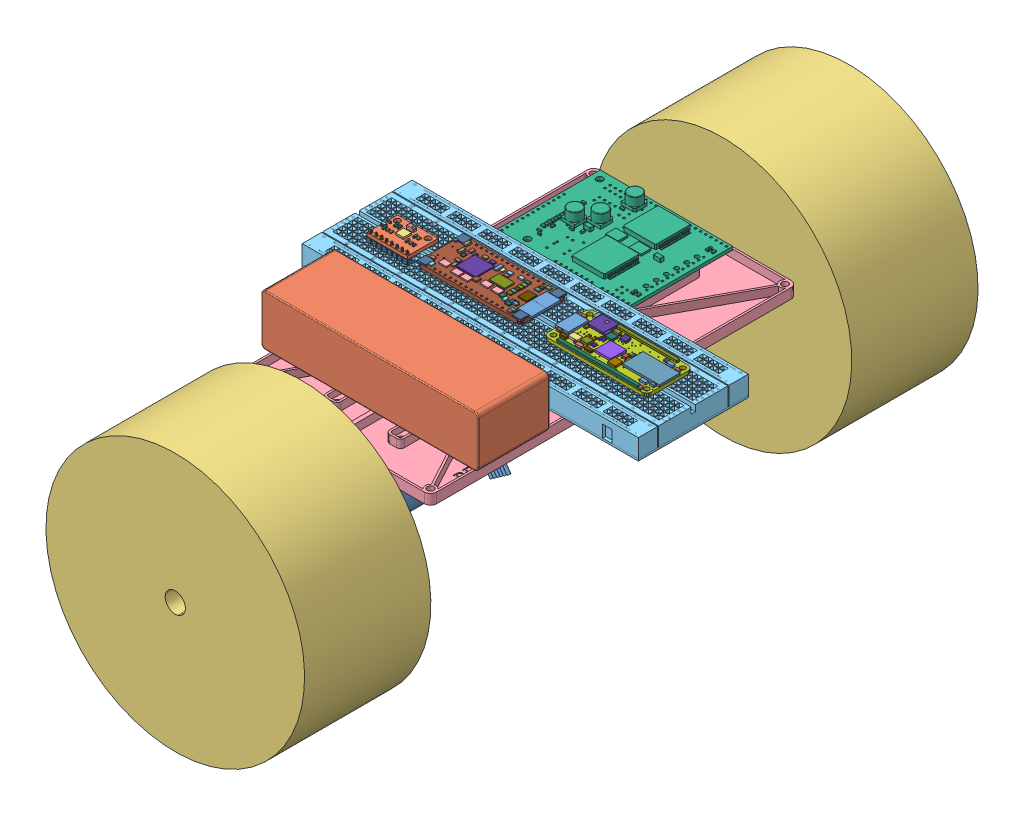
SolidWorks assembly R2-DTF main assembly, configuration Default. Lengths in mm.
Overall size (173.08 173.07 330.68).
140 component instances, 77 part files, 12 mates.
Components (placement in the parent):
- Motor-bracket-wheel-1: Motor-bracket-wheel [Default] at (15.456 46.2296 39.6533) size (173.07 173.07 157.1)
  - 37d-gearmotor-19-30-encoder-1: 37d-gearmotor-19-30-encoder [Default] at (5.5166 54.4384 73.0499) size (36.88 41.23 90.1)
  - pololu-stamped-aluminum-l-bracket-for-37d-mm-metal-gearmotors-1: pololu-stamped-aluminum-l-bracket-for-37d-mm-metal-gearmotors [Default] at (24.4372 55.4358 87.1749) x (-1 0 0) z (0 0 1) size (37.59 39.6 51.2)
  - bigass wheel-1: bigass wheel [Default] at (25.4416 47.4384 119.9749) x (0.492367 -0.870388 0) z (0 0 1) size (127 127 62)
- Motor-bracket-wheel-2: Motor-bracket-wheel [Default] at (66.3304 46.2296 72.9281) x (-1 0 0) z (0 0 -1) size (173.07 173.07 157.1)
  - 37d-gearmotor-19-30-encoder-1: 37d-gearmotor-19-30-encoder [Default] at (5.5166 54.4384 73.0499) size (36.88 41.23 90.1)
  - pololu-stamped-aluminum-l-bracket-for-37d-mm-metal-gearmotors-1: pololu-stamped-aluminum-l-bracket-for-37d-mm-metal-gearmotors [Default] at (24.4372 55.4358 87.1749) x (-1 0 0) z (0 0 1) size (37.59 39.6 51.2)
  - bigass wheel-1: bigass wheel [Default] at (25.4416 47.4384 119.9749) x (0.492367 -0.870388 0) z (0 0 1) size (127 127 62)
- base REV A-1: base REV A [Default] at (40.8942 126.4655 56.2907) x (0 0 -1) z (0 -1 0) size (180 100 8)
- BREADBOARD 60 ROW color-1: BREADBOARD 60 ROW color [Default] at (44.7447 127.4655 53.6357) x (-1 0 0) z (0 1 0) size (165 56 10)
- pololu-dual-vnh5019-motor-driver-shield-1: pololu-dual-vnh5019-motor-driver-shield [Default] at (-1.3408 129.4655 22.0094) x (1 0 0) z (0 1 0) size (65.02 51.31 7.68)
- adafruit feather zero ble rev a-1: adafruit feather zero ble rev a [Default] at (64.8476 139.4655 64.9701) x (1 0 0) z (0 1 0) size (51.25 22.86 3.87)
  - adafruit feather zero ble rev a-1: adafruit feather zero ble rev a [Default] at origin size (50.8 22.86 1.6)
  - Capacitor 0603-1: Capacitor 0603 [Default] at (17.35 12.611 1.63) x (0 1 0) z (1 0 0) size (1.6 0.86 0.86)
  - Capacitor 0603-2: Capacitor 0603 [Default] at (15.97 12.154 1.63) x (0 1 0) z (1 0 0) size (1.6 0.86 0.86)
  - Capacitor 0603-3: Capacitor 0603 [Default] at (11.5188 4.5206 1.63) x (1 0 0) z (0 -1 0) size (1.6 0.86 0.86)
  - Capacitor 0603-4: Capacitor 0603 [Default] at (17.35 7.912 1.63) x (0 1 0) z (1 0 0) size (1.6 0.86 0.86)
  - Capacitor 0603-5: Capacitor 0603 [Default] at (15.953 7.912 1.63) x (0 1 0) z (1 0 0) size (1.6 0.86 0.86)
  - 0805-1: 0805 [Default] at (12.0675 11.176 1.6) x (0 -1 0) z (-1 0 0) size (2.03 0.61 1.28)
  - 0805-2: 0805 [Default] at (7.4505 12.959 1.6) x (0 1 0) z (1 0 0) size (2.03 0.61 1.28)
  - 0805-3: 0805 [Default] at (14.4955 11.624 1.6) x (0 -1 0) z (-1 0 0) size (2.03 0.61 1.28)
  - Capacitor 0805-1: Capacitor 0805 [Default] at (41.767 18.943 1.63) x (1 0 0) z (0 -1 0) size (2 0.76 1.31)
  - Capacitor 0805-2: Capacitor 0805 [Default] at (31.389 12.843 1.63) x (0 -1 0) z (-1 0 0) size (2 0.76 1.31)
  - CHIPLED_0805_NOOUTLINE_ORANGE-1: CHIPLED_0805_NOOUTLINE_ORANGE [Default] at (2.413 5.588 1.6) x (0 -1 0) z (0 0 1) size (1.25 2 1)
  - SOD 123-1: SOD 123 [Default] at (17.78 18.669 1.6) x (-1 0 0) z (0 1 0) size (3.7 1.27 1.6)
  - CHIPLED_0805_NOOUTLINE_RED-1: CHIPLED_0805_NOOUTLINE_RED [Default] at (48.514 17.526 1.6) x (0 -1 0) z (0 0 1) size (1.25 2 1)
  - CHIPLED_0805_NOOUTLINE_RED-2: CHIPLED_0805_NOOUTLINE_RED [Default] at (2.645 17.359 1.6) x (0 1 0) z (0 0 1) size (1.25 2 1)
  - CHIPLED_0805_NOOUTLINE_BLUE-1: CHIPLED_0805_NOOUTLINE_BLUE [Default] at (48.641 5.334 1.6) x (0 -1 0) z (0 0 1) size (1.25 2 1)
  - 1X16_ROUND_JP1_1X16_ROUND-1: 1X16_ROUND_JP1_1X16_ROUND [Default] at (25.4 1.27 1.6) x (-1 0 0) z (0 0 1) size (39.73 1.47 1)
  - 1X12_ROUND_JP3_1X12_ROUND-1: 1X12_ROUND_JP3_1X12_ROUND [Default] at (30.48 21.59 1.6) size (29.57 1.47 1)
  - 0603NO_100K-1: 0603NO_100K [Default] at (15.621 16.129 1.6) x (0 1 0) z (0 0 1) size (3 1.48 1)
  - 0603NO_100K-2: 0603NO_100K [Default] at (22.225 18.669 1.6) size (3 1.48 1)
  - 0603NO_100K-3: 0603NO_100K [Default] at (22.479 17.399 1.6) x (-1 0 0) z (0 0 1) size (3 1.48 1)
  - 0603NO_1K-1: 0603NO_1K [Default] at (6.096 4.191 1.6) size (3 1.48 1)
  - 0603NO_2_2K-1: 0603NO_2_2K [Default] at (44.323 18.288 1.6) size (3 1.48 1)
  - 0603NO_2_2K-2: 0603NO_2_2K [Default] at (5.715 20.828 1.6) x (0 -1 0) z (0 0 1) size (3 1.48 1)
  - 0603NO_2_2K-3: 0603NO_2_2K [Default] at (44.958 4.572 1.6) size (3 1.48 1)
  - 0603NO_10K_-1: 0603NO_10K_ [Default] at (13.843 4.064 1.6) x (-1 0 0) z (0 0 1) size (3 1.48 1)
  - KMR2_SPST_TACTKMR2-1: KMR2_SPST_TACTKMR2 [Default] at (9.398 6.477 1.6) x (-1 0 0) z (0 0 1) size (4.33 2.86 1)
  - TESTPOINT_ROUND_1_5MM_TP1_TESTPOINT_ROUND_1_5MM-1: TESTPOINT_ROUND_1_5MM_TP1_TESTPOINT_ROUND_1_5MM [Default] at (15.367 5.334 0) x (-1 0 0) z (0 0 -1) size (2.2 2.2 1)
  - TESTPOINT_ROUND_1_5MM_TP2_TESTPOINT_ROUND_1_5MM-1: TESTPOINT_ROUND_1_5MM_TP2_TESTPOINT_ROUND_1_5MM [Default] at (17.907 5.334 0) x (-1 0 0) z (0 0 -1) size (2.2 2.2 1)
  - PAD1_5X2_0_SWCLK-1: PAD1_5X2_0_SWCLK [Default] at (43.053 9.525 0) x (-1 0 0) z (0 0 -1) size (2.03 2.46 1)
  - PAD1_5X2_0_SWDIO-1: PAD1_5X2_0_SWDIO [Default] at (40.767 9.525 0) x (-1 0 0) z (0 0 -1) size (2.03 2.46 1)
  - PAD1_5X2_0_SWDIO-2: PAD1_5X2_0_SWDIO [Default] at (38.481 9.525 0) x (-1 0 0) z (0 0 -1) size (2.03 2.46 1)
  - TQFN48_7MM_ATSAMD21G18_QFN-1: TQFN48_7MM_ATSAMD21G18_QFN [Default] at (24.13 9.652 1.6) size (7.81 7.86 1)
  - ADAFRUIT_3_5MM_U_7_ADAFRUIT_3_5MM-1: ADAFRUIT_3_5MM_U_7_ADAFRUIT_3_5MM [Default] at (28.067 3.556 1.6) size (3.79 3.79 1)
  - FEATHERLOGO_U_9_FEATHERLOGO-1: FEATHERLOGO_U_9_FEATHERLOGO [Default] at (37.338 6.604 0) x (-1 0 0) z (0 0 -1) size (24.3 11.26 1)
  - PCBFEATREV040_U_25_PCBFEATREV040-1: PCBFEATREV040_U_25_PCBFEATREV040 [Default] at (29.845 10.668 1.6) size (2.1 2.1 1)
  - BLUEFRUITLOGO_100MM_U_26_BLUEFRUITLOGO_100MM-1: BLUEFRUITLOGO_100MM_U_26_BLUEFRUITLOGO_100MM [Default] at (13.716 7.239 0) x (-1 0 0) z (0 0 -1) size (9.94 10.18 1)
  - FIDUCIAL_1MM_FIDUCIAL__-1: FIDUCIAL_1MM_FIDUCIAL__ [Default] at (10.795 20.066 1.6) x (0 -1 0) z (0 0 1) size (1.75 1.25 1)
  - FIDUCIAL_1MM_FIDUCIAL__-2: FIDUCIAL_1MM_FIDUCIAL__ [Default] at (46.5292 0.896 1.6) x (0 -1 0) z (0 0 1) size (1.75 1.25 1)
  - BLE_MODULE_RAYTAC_MDBT40_MBT40-1: BLE_MODULE_RAYTAC_MDBT40_MBT40 [Default] at (41.656 11.43 1.6) x (0 -1 0) z (0 0 1) size (10.2 18.2 1)
  - SOT235_AP21123_3-1: SOT235_AP21123_3 [Default] at (18.161 15.494 1.6) x (-1 0 0) z (0 0 1) size (3.3 3 1)
  - SOT235_MCP73831T2ACI_OT-1: SOT235_MCP73831T2ACI_OT [Default] at (13.843 7.747 1.6) x (-1 0 0) z (0 0 1) size (3.3 3 1)
  - JSTPH2_JSTPH-1: JSTPH2_JSTPH [Default] at (10.795 19.304 1.6) size (8.2 7.6 1)
  - XTAL3215_32_768-1: XTAL3215_32_768 [Default] at (17.907 4.445 1.6) size (3.26 1.46 1)
  - 4UCONN_20329_V2_MICROUSB-1: 4UCONN_20329_V2_MICROUSB [Default] at (4.445 11.43 1.6) x (0 -1 0) z (0 0 1) size (10.1 6.4 1)
- User Library-GY-521-1: User Library-GY-521 [Valor predeterminado] at (-13.2868 140.2663 36.4208) size (20.32 11.82 15.24)
  - User Library-GY-521_placa-1: User Library-GY-521_placa [Valor predeterminado] at (0.5666 -1.5108 20) size (20 1.67 15)
  - User Library-GY-521_User Library-mpu-6050_qfn-24-1: User Library-GY-521_User Library-mpu-6050_qfn-24 [Default] at (-1.4334 0.1092 17.5) x (0 0 1) z (-1 0 0) size (4.04 0.9 4.04)
  - User Library-GY-521_User Library-CAP_TANT_3216-18_A_case-1-1: User Library-GY-521_User Library-CAP_TANT_3216-18_A_case-1 [Default] at (0.3666 0.0692 15.4) x (-1 0 0) z (0 0 -1) size (3.4 1.7 1.8)
  - User Library-GY-521_User Library-sot353-1: User Library-GY-521_User Library-sot353 [По умолчанию] at (-8.2834 0.0892 20.35) x (-1 0 0) z (0 1 0) size (2.1 2.3 1)
  - User Library-GY-521_User Library-0603(1608M) Cap-1: User Library-GY-521_User Library-0603(1608M) Cap [Default] at (4.4603 0.0892 17.5499) x (0 0 -1) z (1 0 0) size (2.01 0.8 0.79)
  - User Library-GY-521_User Library-0603(1608M) Cap-2: User Library-GY-521_User Library-0603(1608M) Cap [Default] at (4.4603 0.0892 21.4501) x (0 0 -1) z (1 0 0) size (2.01 0.8 0.79)
  - User Library-GY-521_User Library-RESC1608X05N-1: User Library-GY-521_User Library-RESC1608X05N [Default] at (6.174 0.0892 17.5499) x (0 0 -1) z (0 1 0) size (1.55 0.85 0.45)
  - User Library-GY-521_User Library-RESC1608X05N-2: User Library-GY-521_User Library-RESC1608X05N [Default] at (6.174 0.0892 21.4501) x (0 0 -1) z (0 1 0) size (1.55 0.85 0.45)
  - User Library-GY-521_User Library-LED SMD0603-1: User Library-GY-521_User Library-LED SMD0603 [Default] at (7.8618 0.0844 20.8327) x (1 0 0) z (0 1 0) size (0.73 1.65 0.68)
  - User Library-GY-521_User Library-RESC1608X05N-3: User Library-GY-521_User Library-RESC1608X05N [Default] at (-3.3534 0.0892 21.4501) x (0 0 -1) z (0 1 0) size (1.55 0.85 0.45)
  - User Library-GY-521_User Library-RESC1608X05N-4: User Library-GY-521_User Library-RESC1608X05N [Default] at (-5.0934 0.0892 21.4501) x (0 0 -1) z (0 1 0) size (1.55 0.85 0.45)
  - User Library-GY-521_User Library-0603(1608M) Cap-3: User Library-GY-521_User Library-0603(1608M) Cap [Default] at (-6.8071 0.0892 21.4501) x (0 0 -1) z (1 0 0) size (2.01 0.8 0.79)
  - User Library-GY-521_User Library-0603(1608M) Cap-4: User Library-GY-521_User Library-0603(1608M) Cap [Default] at (-8.2834 0.0892 17.8063) size (2.01 0.8 0.79)
  - User Library-GY-521_User Library-0603(1608M) Cap-5: User Library-GY-521_User Library-0603(1608M) Cap [Default] at (-5.0145 0.0892 17.5499) x (0 0 -1) z (1 0 0) size (2.01 0.8 0.79)
  - User Library-GY-521_User Library-0603(1608M) Cap-6: User Library-GY-521_User Library-0603(1608M) Cap [Default] at (-3.3271 0.0892 17.5499) x (0 0 -1) z (1 0 0) size (2.01 0.8 0.79)
  - User Library-GY-521_User Library-Header_Male_8Pin-1: User Library-GY-521_User Library-Header_Male_8Pin [Default] at (-8.3234 -1.5108 26.5) x (1 0 0) z (0 -1 0) size (20.32 2.49 11.54)
    - User Library-GY-521_User Library-Header_Male_8Pin_PinArray-1: User Library-GY-521_User Library-Header_Male_8Pin_PinArray [Default] at origin size (18.42 0.64 11.54)
    - User Library-GY-521_User Library-Header_Male_8Pin_BodyArray-1: User Library-GY-521_User Library-Header_Male_8Pin_BodyArray [Default] at origin size (20.32 2.49 2.29)
- adafruit ezsfx with amp-1: adafruit ezsfx with amp [Default] at (2.9992 139.4655 65.0779) x (1 0 0) z (0 1 0) size (52.82 22.86 3.87)
  - adafruit ezsfx with amp-1: adafruit ezsfx with amp [Default] at origin size (50.8 22.86 2)
  - Capacitor 0805-1: Capacitor 0805 [Default] at (40.406 6.239 1.63) x (0 -1 0) z (-1 0 0) size (2 0.76 1.31)
  - Capacitor 0805-2: Capacitor 0805 [Default] at (8.997 14.081 1.63) x (0 1 0) z (1 0 0) size (2 0.76 1.31)
  - Capacitor 0805-3: Capacitor 0805 [Default] at (11.831 16.78 1.63) x (0 -1 0) z (-1 0 0) size (2 0.76 1.31)
  - 0805_10MGAP_10UF-1: 0805_10MGAP_10UF [Default] at (36.703 16.002 1.6) x (-1 0 0) z (0 0 1) size (2.2 1.45 1)
  - 0805_10MGAP_10UF-2: 0805_10MGAP_10UF [Default] at (15.367 18.288 1.6) x (-1 0 0) z (0 0 1) size (2.2 1.45 1)
  - 0805_10MGAP_10UF-3: 0805_10MGAP_10UF [Default] at (10.922 7.62 1.6) x (0 -1 0) z (0 0 1) size (2.2 1.45 1)
  - 0805NO_1UF-1: 0805NO_1UF [Default] at (9.906 10.287 1.6) x (-1 0 0) z (0 0 1) size (2.2 1.45 1)
  - 0805NO_1UF-2: 0805NO_1UF [Default] at (9.271 17.653 1.6) x (0 -1 0) z (0 0 1) size (2.2 1.45 1)
  - 0805-1: 0805 [Default] at (42.545 7.1095 1.6) x (-1 0 0) z (0 1 0) size (2.03 0.61 1.28)
  - 0805NO_0_1_F-1: 0805NO_0_1_F [Default] at (42.037 17.399 1.6) x (-1 0 0) z (0 0 1) size (2.2 1.45 1)
  - 0805NO_0_1_F-2: 0805NO_0_1_F [Default] at (36.576 10.922 1.6) size (2.2 1.45 1)
  - 0805NO_0_1_F-3: 0805NO_0_1_F [Default] at (42.545 5.969 1.6) x (-1 0 0) z (0 0 1) size (2.2 1.45 1)
  - 0805NO_4_7NF-1: 0805NO_4_7NF [Default] at (40.64 4.191 1.6) size (2.2 1.45 1)
  - 0805NO_4_7NF-2: 0805NO_4_7NF [Default] at (36.449 17.907 1.6) size (2.2 1.45 1)
  - 0805NO_1_F-1: 0805NO_1_F [Default] at (36.576 9.144 1.6) size (2.2 1.45 1)
  - 0805NO_1_F-2: 0805NO_1_F [Default] at (36.703 14.224 1.6) size (2.2 1.45 1)
  - 1X14CB_CONTROL-1: 1X14CB_CONTROL [Default] at (24.13 21.59 1.6) size (33.53 0.51 0)
  - SOD323_1N4148-1: SOD323_1N4148 [Default] at (19.304 18.034 1.6) x (-1 0 0) z (0 0 1) size (2.2 1.5 1)
  - SOD 123-1: SOD 123 [Default] at (5.207 19.558 1.6) x (0 1 0) z (1 0 0) size (3.7 1.27 1.6)
  - SOD 123-2: SOD 123 [Default] at (6.858 15.113 1.6) x (0 -1 0) z (-1 0 0) size (3.7 1.27 1.6)
  - _0805MP_FERRITE-1: _0805MP_FERRITE [Default] at (42.037 19.05 1.6) size (2 1.3 1)
  - _0805MP_FERRITE-2: _0805MP_FERRITE [Default] at (36.703 12.573 1.6) size (2 1.3 1)
  - FIDUCIAL_1MM_FIDUCIAL__-1: FIDUCIAL_1MM_FIDUCIAL__ [Default] at (44.45 1.016 1.6) size (1.75 1.25 1)
  - FIDUCIAL_1MM_FIDUCIAL__-2: FIDUCIAL_1MM_FIDUCIAL__ [Default] at (0.762 17.907 1.6) size (1.75 1.25 1)
  - 1X14CB_GPIO-1: 1X14CB_GPIO [Default] at (24.13 1.27 1.6) x (-1 0 0) z (0 0 1) size (33.53 0.51 0)
  - CHIPLED_0805_NOOUTLINE_RED-1: CHIPLED_0805_NOOUTLINE_RED [Default] at (28.321 15.748 1.6) x (0 1 0) z (0 0 1) size (1.25 2 1)
  - TERMBLOCK_1X23_5MM_3_5MM-1: TERMBLOCK_1X23_5MM_3_5MM [Default] at (48.641 7.747 1.6) x (0 1 0) z (0 0 1) size (7.1 7.1 1)
  - TERMBLOCK_1X23_5MM_3_5MM-2: TERMBLOCK_1X23_5MM_3_5MM [Default] at (48.641 14.859 1.6) x (0 1 0) z (0 0 1) size (7.1 7.1 1)
  - CHIPLED_0805_NOOUTLINE_GREEN-1: CHIPLED_0805_NOOUTLINE_GREEN [Default] at (2.54 5.334 1.6) x (0 1 0) z (0 0 1) size (1.25 2 1)
  - 0805NO_1M-1: 0805NO_1M [Default] at (25.146 17.018 1.6) x (0 -1 0) z (0 0 1) size (2.2 1.45 1)
  - RESPACK_4X0603_100K-1: RESPACK_4X0603_100K [Default] at (8.001 5.842 1.6) size (3.8 2.8 1)
  - RESPACK_4X0603_100K-2: RESPACK_4X0603_100K [Default] at (14.859 4.953 1.6) x (-1 0 0) z (0 0 1) size (3.8 2.8 1)
  - RESPACK_4X0603_100K-3: RESPACK_4X0603_100K [Default] at (19.431 4.953 1.6) x (-1 0 0) z (0 0 1) size (3.8 2.8 1)
  - RESPACK_4X0603_100K-4: RESPACK_4X0603_100K [Default] at (32.512 7.112 1.6) size (3.8 2.8 1)
  - RESPACK_4X0603_100K-5: RESPACK_4X0603_100K [Default] at (27.178 7.112 1.6) x (-1 0 0) z (0 0 1) size (3.8 2.8 1)
  - 0805NO_470-1: 0805NO_470 [Default] at (37.973 5.461 1.6) x (0 -1 0) z (0 0 1) size (2.2 1.45 1)
  - 0805NO_470-2: 0805NO_470 [Default] at (33.02 18.288 1.6) size (2.2 1.45 1)
  - 0805NO_470-3: 0805NO_470 [Default] at (5.08 2.286 1.6) x (0 1 0) z (0 0 1) size (2.2 1.45 1)
  - 0805NO_470-4: 0805NO_470 [Default] at (28.194 17.526 1.6) size (2.2 1.45 1)
  - 0805NO_100K-1: 0805NO_100K [Default] at (44.45 2.794 1.6) size (2.2 1.45 1)
  - 0805NO_100K-2: 0805NO_100K [Default] at (43.942 20.701 1.6) x (-1 0 0) z (0 0 1) size (2.2 1.45 1)
  - SOLDERJUMPER_ARROW_NOPASTE_SJ1_SOLDERJUMPER_ARROW_NOPASTE-1: SOLDERJUMPER_ARROW_NOPASTE_SJ1_SOLDERJUMPER_ARROW_NOPASTE [Default] at (43.815 2.159 0) x (0 1 0) z (0 0 -1) size (3.3 2.13 1)
  - SOLDERJUMPER_CLOSEDWIRE_SJ2_SOLDERJUMPER_CLOSEDWIRE-1: SOLDERJUMPER_CLOSEDWIRE_SJ2_SOLDERJUMPER_CLOSEDWIRE [Default] at (44.704 20.955 0) x (0 -1 0) z (0 0 -1) size (3.3 2.13 1)
  - B1_27_PTR1B1_27-1: B1_27_PTR1B1_27 [Default] at (31.242 11.303 0) x (-1 0 0) z (0 0 -1) size (1.27 0.64 1)
  - B1_27_PTR1B1_27-2: B1_27_PTR1B1_27 [Default] at (22.606 14.859 0) x (-1 0 0) z (0 0 -1) size (1.27 0.64 1)
  - B1_27_PTR1B1_27-3: B1_27_PTR1B1_27 [Default] at (27.813 11.43 0) x (-1 0 0) z (0 0 -1) size (1.27 0.64 1)
  - MOUNTINGHOLE_2_5_PLATED_MOUNTINGHOLE2_5-1: MOUNTINGHOLE_2_5_PLATED_MOUNTINGHOLE2_5 [Default] at (2.159 20.701 1.6) size (4.2 4.2 1)
  - MOUNTINGHOLE_2_5_PLATED_MOUNTINGHOLE2_5-2: MOUNTINGHOLE_2_5_PLATED_MOUNTINGHOLE2_5 [Default] at (2.159 2.159 1.6) size (4.2 4.2 1)
  - MOUNTINGHOLE_2_5_PLATED_MOUNTINGHOLE2_5-3: MOUNTINGHOLE_2_5_PLATED_MOUNTINGHOLE2_5 [Default] at (48.641 20.701 1.6) size (4.2 4.2 1)
  - MOUNTINGHOLE_2_5_PLATED_MOUNTINGHOLE2_5-4: MOUNTINGHOLE_2_5_PLATED_MOUNTINGHOLE2_5 [Default] at (48.641 2.159 1.6) size (4.2 4.2 1)
  - ADAFRUIT_2_5MM_U_11_ADAFRUIT_2_5MM-1: ADAFRUIT_2_5MM_U_11_ADAFRUIT_2_5MM [Default] at (23.622 5.588 1.6) x (0 1 0) z (0 0 1) size (2.44 2.43 1)
  - SYMBOL_PLUS_U_12_SYMBOL_PLUS-1: SYMBOL_PLUS_U_12_SYMBOL_PLUS [Default] at (9.144 8.509 0) x (-1 0 0) z (0 0 -1) size (1.77 1.77 1)
  - SYMBOL_MINUS_U_13_SYMBOL_MINUS-1: SYMBOL_MINUS_U_13_SYMBOL_MINUS [Default] at (9.144 14.351 0) x (-1 0 0) z (0 0 -1) size (1.77 1.77 1)
  - ADAFRUIT_TEXT_20MM_U_14_ADAFRUIT_TEXT_20MM-1: ADAFRUIT_TEXT_20MM_U_14_ADAFRUIT_TEXT_20MM [Default] at (44.704 12.573 0) x (-1 0 0) z (0 0 -1) size (19.57 7.63 1)
  - PCBFEATREV040_U_15_PCBFEATREV040-1: PCBFEATREV040_U_15_PCBFEATREV040 [Default] at (35.814 6.35 1.6) size (2.1 2.1 1)
  - SOIC8_208MIL_MX25L1606-1: SOIC8_208MIL_MX25L1606 [Default] at (29.718 11.938 1.6) x (0 1 0) z (0 0 1) size (4.9 7.63 1)
  - LQFP48_VS1000-1: LQFP48_VS1000 [Default] at (16.764 11.938 1.6) x (0 1 0) z (0 0 1) size (9.15 9.6 1)
  - WQFN20_TS2012-1: WQFN20_TS2012 [Default] at (42.291 12.446 1.6) size (4.2 5.08 1)
  - 4UCONN_20329_MICRO-1: 4UCONN_20329_MICRO [Default] at (4.318 11.43 1.6) x (0 -1 0) z (0 0 1) size (10.1 6.4 0)
  - JSTPH2_JSTPH-1: JSTPH2_JSTPH [Default] at (3.556 11.43 0) x (0 -1 0) z (0 0 -1) size (8.2 7.6 1)
  - RESONATORSMD_12MHZ-1: RESONATORSMD_12MHZ [Default] at (22.987 17.145 1.6) x (0 -1 0) z (0 0 1) size (3.7 1.5 1)
- lipo 3s battery-1: lipo 3s battery [Default] at (39.6476 151.4655 107.425) x (-1 0 0) z (0 -1 0) size (106.5 35 25)
Mates (geometry in assembly coordinates):
- Coincident2: coincident anti-aligned: plane of Motor-bracket-wheel-1/pololu-stamped-aluminum-l-bracket-for-37d-mm-metal-gearmotors-1 through (22.0972 121.4655 132.6282) normal (0 1 0); plane of base REV A-1 through (40.8942 121.4655 56.2907) normal (0 -1 0)
- Coincident3: coincident anti-aligned: plane of Motor-bracket-wheel-2/pololu-stamped-aluminum-l-bracket-for-37d-mm-metal-gearmotors-1 through (59.6892 121.4655 -20.0468) normal (0 1 0); plane of base REV A-1 through (40.8942 121.4655 56.2907) normal (0 -1 0)
- Concentric1: concentric aligned: cylinder of Motor-bracket-wheel-1/pololu-stamped-aluminum-l-bracket-for-37d-mm-metal-gearmotors-1 through (56.5142 121.4655 126.2907) axis (0 -1 0) radius 1.5875; cylinder of base REV A-1 through (56.5142 126.4655 126.2907) axis (0 -1 0) radius 1.59
- Concentric5: concentric aligned: cylinder of Motor-bracket-wheel-1/pololu-stamped-aluminum-l-bracket-for-37d-mm-metal-gearmotors-1 through (56.5142 121.4655 88.1907) axis (0 -1 0) radius 1.5875; cylinder of base REV A-1 through (56.5142 126.4655 88.1907) axis (0 -1 0) radius 1.59
- Concentric6: concentric aligned: cylinder of Motor-bracket-wheel-2/pololu-stamped-aluminum-l-bracket-for-37d-mm-metal-gearmotors-1 through (56.5142 121.4655 -13.7093) axis (0 -1 0) radius 1.5875; cylinder of base REV A-1 through (56.5142 126.4655 -13.7093) axis (0 -1 0) radius 1.59
- Concentric7: concentric aligned: cylinder of Motor-bracket-wheel-2/pololu-stamped-aluminum-l-bracket-for-37d-mm-metal-gearmotors-1 through (56.5142 121.4655 24.3907) axis (0 -1 0) radius 1.5875; cylinder of base REV A-1 through (56.5142 126.4655 24.3907) axis (0 -1 0) radius 1.59
- Coincident4: coincident anti-aligned: plane of base REV A-1 through (40.8942 126.4655 56.2907) normal (0 1 0); plane of BREADBOARD 60 ROW color-1 through (44.7447 126.4655 53.6357) normal (0 -1 0)
- Distance1: distance = 2 mm anti-aligned: plane of adafruit feather zero ble rev a-1/FEATHERLOGO_U_9_FEATHERLOGO-1 through (102.1856 138.4655 58.3661) normal (0 -1 0); plane of BREADBOARD 60 ROW color-1 through (44.7447 136.4655 53.6357) normal (0 1 0)
- Coincident9: coincident anti-aligned: plane of base REV A-1 through (40.8942 126.4655 56.2907) normal (0 1 0); plane of lipo 3s battery-1 through (39.6476 126.4655 107.425) normal (0 -1 0)
- Coincident10: coincident anti-aligned: plane of BREADBOARD 60 ROW color-1 through (44.7447 136.4655 53.6357) normal (0 1 0); plane of User Library-GY-521-1/User Library-GY-521_User Library-Header_Male_8Pin-1/User Library-GY-521_User Library-Header_Male_8Pin_BodyArray-1 through (-22.8803 136.4655 64.1658) normal (0 -1 0)
- Distance2: distance = 3 mm anti-aligned: plane of adafruit ezsfx with amp-1/adafruit ezsfx with amp-1 through (2.9992 139.4655 65.0779) normal (0 -1 0); plane of BREADBOARD 60 ROW color-1 through (44.7447 136.4655 53.6357) normal (0 1 0)
- Coincident13: coincident anti-aligned: plane of base REV A-1 through (10.1159 129.4655 17.6071) normal (0 1 0); plane of pololu-dual-vnh5019-motor-driver-shield-1 through (-1.3408 129.4655 22.0094) normal (0 -1 0)
